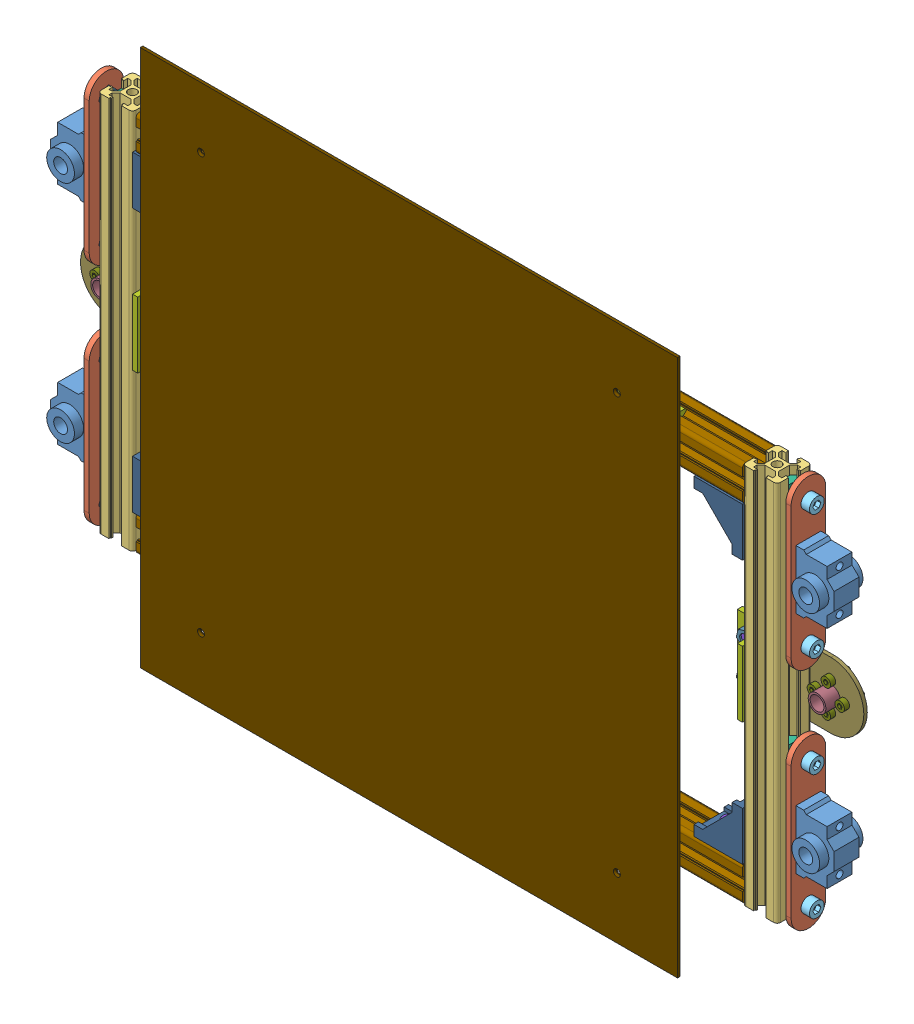
SolidWorks assembly 023Z轴平台-1, configuration 默认. Lengths in mm.
Overall size (452 310 46.5).
135 component instances, 18 part files, 83 mates.
Components (placement in the parent):
- SCS箱式直线两孔光轴短滑块SCS8-1: SCS箱式直线两孔光轴短滑块SCS8 [默认] at (43.7707 34.0892 10.8311) x (0 1 0) z (1 0 0) size (34 25 22)
- 不锈钢钢片件-1: 不锈钢钢片件 [默认] at (15.359 -82.3814 20.8311) x (0 1 0) z (0 0 1) size (96 3 20)
- 不锈钢钢片件-2: 不锈钢钢片件 [默认] at (15.359 -212.3814 20.8311) x (0 1 0) z (0 0 1) size (96 3 20)
- SCS箱式直线两孔光轴短滑块SCS8-2: SCS箱式直线两孔光轴短滑块SCS8 [默认] at (43.7707 -95.9108 10.8311) x (0 1 0) z (1 0 0) size (34 25 22)
- OB6_2020_220-1: OB6_2020_220 [默认] at (-2.641 10.6186 10.8311) x (1 0 0) z (0 -1 0) size (20 20 220)
- M4_10-1: M4_10 [默认] at (22.359 -22.3814 10.8311) x (0 1 0) z (0 0 1) size (7 13.91 7)
- M4_10-2: M4_10 [默认] at (22.359 -46.3814 10.8311) x (0 1 0) z (0 0 1) size (7 13.91 7)
- M5_12-1: M5_12 [默认] at (3.359 1.6186 10.8311) x (0 -1 0) z (0 0 1) size (8.5 16.91 8.5)
- M5_12-5: M5_12 [默认] at (3.359 -70.3814 10.8311) x (0 -1 0) z (0 0 1) size (8.5 16.91 8.5)
- 欧标20M5滑块螺母-1: 欧标20M5滑块螺母 [默认] at (2.259 6.3686 15.5811) x (0 -1 0) z (0 0 1) size (9.5 4.5 9.5)
- 欧标20M5滑块螺母-2: 欧标20M5滑块螺母 [默认] at (2.259 -65.6314 15.5811) x (0 -1 0) z (0 0 1) size (9.5 4.5 9.5)
- 欧标20M5滑块螺母-3: 欧标20M5滑块螺母 [默认] at (2.259 -195.6314 15.5811) x (0 -1 0) z (0 0 1) size (9.5 4.5 9.5)
- 欧标20M5滑块螺母-4: 欧标20M5滑块螺母 [默认] at (2.259 -123.6314 15.5811) x (0 -1 0) z (0 0 1) size (9.5 4.5 9.5)
- M5_12-6: M5_12 [默认] at (3.359 -200.3814 10.8311) x (0 -1 0) z (0 0 1) size (8.5 16.91 8.5)
- M5_12-4: M5_12 [默认] at (3.359 -128.3814 10.8311) x (0 -1 0) z (0 0 1) size (8.5 16.91 8.5)
- M4_10-3: M4_10 [默认] at (22.359 -176.3814 10.8311) x (0 1 0) z (0 0 1) size (7 13.91 7)
- M4_10-4: M4_10 [默认] at (22.359 -152.3814 10.8311) x (0 1 0) z (0 0 1) size (7 13.91 7)
- 可调平行连接角件2040_90度直角-1: 可调平行连接角件2040_90度直角 [默认] at (-12.641 -118.3814 0.8311) x (0 1 0) z (1 0 0) size (38 20 20)
- M5_8-5: M5_8 [默认] at (-7.641 -109.3814 10.8311) x (0 1 0) z (0 0 1) size (8.5 12.91 8.5)
- M5_8-6: M5_8 [默认] at (-7.641 -89.3814 10.8311) x (0 1 0) z (0 0 1) size (8.5 12.91 8.5)
- 欧标20M5滑块螺母-5: 欧标20M5滑块螺母 [默认] at (-7.541 -114.1314 15.5811) x (0 1 0) z (0 0 1) size (9.5 4.5 9.5)
- 欧标20M5滑块螺母-6: 欧标20M5滑块螺母 [默认] at (-7.541 -94.1314 15.5811) x (0 1 0) z (0 0 1) size (9.5 4.5 9.5)
- M5_12-7: M5_12 [默认] at (-380.641 -200.3814 10.8311) x (0 1 0) z (0 0 1) size (8.5 16.91 8.5)
- M4_10-5: M4_10 [默认] at (-399.641 -176.3814 10.8311) x (0 1 0) z (0 0 -1) size (7 13.91 7)
- 欧标20M5滑块螺母-7: 欧标20M5滑块螺母 [默认] at (-379.541 -65.6314 6.0811) x (0 -1 0) z (0 0 -1) size (9.5 4.5 9.5)
- M5_12-8: M5_12 [默认] at (-380.641 -70.3814 10.8311) x (0 1 0) z (0 0 1) size (8.5 16.91 8.5)
- M5_12-9: M5_12 [默认] at (-380.641 -128.3814 10.8311) x (0 1 0) z (0 0 1) size (8.5 16.91 8.5)
- 欧标20M5滑块螺母-8: 欧标20M5滑块螺母 [默认] at (-379.541 -123.6314 6.0811) x (0 -1 0) z (0 0 -1) size (9.5 4.5 9.5)
- 欧标20M5滑块螺母-9: 欧标20M5滑块螺母 [默认] at (-379.541 -195.6314 6.0811) x (0 -1 0) z (0 0 -1) size (9.5 4.5 9.5)
- M4_10-6: M4_10 [默认] at (-399.641 -152.3814 10.8311) x (0 1 0) z (0 0 -1) size (7 13.91 7)
- 欧标20M5滑块螺母-10: 欧标20M5滑块螺母 [默认] at (-379.541 6.3686 6.0811) x (0 -1 0) z (0 0 -1) size (9.5 4.5 9.5)
- M4_10-7: M4_10 [默认] at (-399.641 -46.3814 10.8311) x (0 1 0) z (0 0 -1) size (7 13.91 7)
- OB6_2020_220-2: OB6_2020_220 [默认] at (-374.641 -209.3814 10.8311) x (-1 0 0) z (0 1 0) size (20 20 220)
- SCS箱式直线两孔光轴短滑块SCS8-3: SCS箱式直线两孔光轴短滑块SCS8 [默认] at (-421.0528 -232.8519 10.8311) x (0 -1 0) z (-1 0 0) size (34 25 22)
- 不锈钢钢片件-3: 不锈钢钢片件 [默认] at (-392.641 -212.3814 0.8311) x (0 1 0) z (0 0 -1) size (96 3 20)
- 不锈钢钢片件-4: 不锈钢钢片件 [默认] at (-392.641 -82.3814 0.8311) x (0 1 0) z (0 0 -1) size (96 3 20)
- 欧标20M5滑块螺母-11: 欧标20M5滑块螺母 [默认] at (-369.741 -114.1314 6.0811) x (0 1 0) z (0 0 -1) size (9.5 4.5 9.5)
- M5_8-10: M5_8 [默认] at (-369.641 -89.3814 10.8311) x (0 -1 0) z (0 0 1) size (8.5 12.91 8.5)
- M5_8-11: M5_8 [默认] at (-369.641 -109.3814 10.8311) x (0 -1 0) z (0 0 1) size (8.5 12.91 8.5)
- M5_12-12: M5_12 [默认] at (-380.641 1.6186 10.8311) x (0 1 0) z (0 0 1) size (8.5 16.91 8.5)
- M4_10-8: M4_10 [默认] at (-399.641 -22.3814 10.8311) x (0 1 0) z (0 0 -1) size (7 13.91 7)
- 欧标20M5滑块螺母-12: 欧标20M5滑块螺母 [默认] at (-369.741 -94.1314 6.0811) x (0 1 0) z (0 0 -1) size (9.5 4.5 9.5)
- SCS箱式直线两孔光轴短滑块SCS8-4: SCS箱式直线两孔光轴短滑块SCS8 [默认] at (-421.0528 -102.8519 10.8311) x (0 -1 0) z (-1 0 0) size (34 25 22)
- 可调平行连接角件2040_90度直角-2: 可调平行连接角件2040_90度直角 [默认] at (-364.641 -80.3814 0.8311) x (0 -1 0) z (-1 0 0) size (38 20 20)
- OB6_2020_350-1: OB6_2020_350 [默认] at (-362.641 0.6186 10.8311) x (0 0 -1) z (1 0 0) size (20 20 350)
- OB6_2020_350-2: OB6_2020_350 [默认] at (-12.641 -199.3814 10.8311) x (0 0 -1) z (-1 0 0) size (20 20 350)
- 20角件加螺丝-1: 20角件加螺丝 [默认] at (-24.6902 -25.7024 40.3311) x (0 -1 0) z (0 0 -1) size (34 34 20)
  - 角件20-1: 角件20 [默认] at (-16.321 -12.0491 19.5) size (29.5 29.5 20)
  - 欧标20M5T形螺母-1: 欧标20M5T形螺母 [默认] at (3.679 -18.0491 34.5) x (0 0 -1) z (1 0 0) size (10 4.5 6)
  - M5_8-1: M5_8 [默认] at (0.679 -16.0491 29.5) size (8.5 12.91 8.5)
  - 欧标20M5T形螺母-2: 欧标20M5T形螺母 [默认] at (-22.321 1.9509 34.5) x (0 0 -1) z (0 -1 0) size (10 4.5 6)
  - M5_8-2: M5_8 [默认] at (-20.321 4.9509 29.5) x (0 -1 0) z (0 0 1) size (8.5 12.91 8.5)
- 20角件加螺丝-2: 20角件加螺丝 [默认] at (-352.5919 -25.7024 -18.6689) x (0 -1 0) z (0 0 1) size (34 34 20)
  - 角件20-1: 角件20 [默认] at (-16.321 -12.0491 19.5) size (29.5 29.5 20)
  - 欧标20M5T形螺母-1: 欧标20M5T形螺母 [默认] at (3.679 -18.0491 34.5) x (0 0 -1) z (1 0 0) size (10 4.5 6)
  - M5_8-1: M5_8 [默认] at (0.679 -16.0491 29.5) size (8.5 12.91 8.5)
  - 欧标20M5T形螺母-2: 欧标20M5T形螺母 [默认] at (-22.321 1.9509 34.5) x (0 0 -1) z (0 -1 0) size (10 4.5 6)
  - M5_8-2: M5_8 [默认] at (-20.321 4.9509 29.5) x (0 -1 0) z (0 0 1) size (8.5 12.91 8.5)
- 20角件加螺丝-3: 20角件加螺丝 [默认] at (-24.6902 -173.0603 -18.6689) x (0 1 0) z (0 0 1) size (34 34 20)
  - 角件20-1: 角件20 [默认] at (-16.321 -12.0491 19.5) size (29.5 29.5 20)
  - 欧标20M5T形螺母-1: 欧标20M5T形螺母 [默认] at (3.679 -18.0491 34.5) x (0 0 -1) z (1 0 0) size (10 4.5 6)
  - M5_8-1: M5_8 [默认] at (0.679 -16.0491 29.5) size (8.5 12.91 8.5)
  - 欧标20M5T形螺母-2: 欧标20M5T形螺母 [默认] at (-22.321 1.9509 34.5) x (0 0 -1) z (0 -1 0) size (10 4.5 6)
  - M5_8-2: M5_8 [默认] at (-20.321 4.9509 29.5) x (0 -1 0) z (0 0 1) size (8.5 12.91 8.5)
- 20角件加螺丝-4: 20角件加螺丝 [默认] at (-352.5919 -173.0603 40.3311) x (0 1 0) z (0 0 -1) size (34 34 20)
  - 角件20-1: 角件20 [默认] at (-16.321 -12.0491 19.5) size (29.5 29.5 20)
  - 欧标20M5T形螺母-1: 欧标20M5T形螺母 [默认] at (3.679 -18.0491 34.5) x (0 0 -1) z (1 0 0) size (10 4.5 6)
  - M5_8-1: M5_8 [默认] at (0.679 -16.0491 29.5) size (8.5 12.91 8.5)
  - 欧标20M5T形螺母-2: 欧标20M5T形螺母 [默认] at (-22.321 1.9509 34.5) x (0 0 -1) z (0 -1 0) size (10 4.5 6)
  - M5_8-2: M5_8 [默认] at (-20.321 4.9509 29.5) x (0 -1 0) z (0 0 1) size (8.5 12.91 8.5)
- Z轴丝杆连接片-1: Z轴丝杆连接片 [默认] at (18.359 -99.3814 0.8311) x (-1 0 0) z (0 -1 0) size (69 2 38)
- 8MM丝杆T形螺母-1: 8MM丝杆T形螺母 [默认] at (18.359 -99.3814 8.8311) x (1 0 0) z (0 1 0) size (22 15.5 22)
- Z轴丝杆连接片-2: Z轴丝杆连接片 [默认] at (-395.641 -99.3814 0.8311) x (1 0 0) z (0 1 0) size (69 2 38)
- 8MM丝杆T形螺母-2: 8MM丝杆T形螺母 [默认] at (-395.641 -99.3814 8.8311) x (-1 0 0) z (0 -1 0) size (22 15.5 22)
- M5螺母-1: M5螺母 [默认] at (12.359 1.6186 10.8311) x (0 1 0) z (0 0 1) size (8.9 3.9 8.95)
- M5螺母-2: M5螺母 [默认] at (12.359 -70.3814 10.8311) x (0 1 0) z (0 0 1) size (8.9 3.9 8.95)
- M5螺母-3: M5螺母 [默认] at (12.359 -128.3814 10.8311) x (0 1 0) z (0 0 1) size (8.9 3.9 8.95)
- M5螺母-4: M5螺母 [默认] at (12.359 -200.3814 10.8311) x (0 1 0) z (0 0 1) size (8.9 3.9 8.95)
- M5螺母-5: M5螺母 [默认] at (-385.741 1.6186 10.8311) x (0 1 0) z (0 0 1) size (8.9 3.9 8.95)
- M5螺母-6: M5螺母 [默认] at (-385.741 -70.3814 10.8311) x (0 1 0) z (0 0 1) size (8.9 3.9 8.95)
- M5螺母-7: M5螺母 [默认] at (-385.741 -128.3814 10.8311) x (0 1 0) z (0 0 1) size (8.9 3.9 8.95)
- M5螺母-8: M5螺母 [默认] at (-385.741 -200.3814 10.8311) x (0 1 0) z (0 0 1) size (8.9 3.9 8.95)
- M5_6-13: M5_6 [默认] at (-2.541 -109.1314 4.8311) x (1 0 0) z (0 1 0) size (8.5 10.91 8.5)
- 欧标20M5滑块螺母-13: 欧标20M5滑块螺母 [默认] at (-7.291 -113.8814 5.9311) x (0 1 0) z (-1 0 0) size (9.5 4.5 9.5)
- 欧标20M5滑块螺母-14: 欧标20M5滑块螺母 [默认] at (-7.291 -93.8814 5.9311) x (0 1 0) z (-1 0 0) size (9.5 4.5 9.5)
- M5_6-14: M5_6 [默认] at (-2.541 -89.1314 4.8311) x (1 0 0) z (0 1 0) size (8.5 10.91 8.5)
- M5_6-15: M5_6 [默认] at (-374.741 -109.1314 4.8311) x (-1 0 0) z (0 -1 0) size (8.5 10.91 8.5)
- 欧标20M5滑块螺母-15: 欧标20M5滑块螺母 [默认] at (-379.491 -113.8814 5.9311) x (0 1 0) z (-1 0 0) size (9.5 4.5 9.5)
- 欧标20M5滑块螺母-16: 欧标20M5滑块螺母 [默认] at (-379.491 -93.8814 5.9311) x (0 1 0) z (-1 0 0) size (9.5 4.5 9.5)
- M5_6-16: M5_6 [默认] at (-374.741 -89.1314 4.8311) x (-1 0 0) z (0 -1 0) size (8.5 10.91 8.5)
- M5_8-15: M5_8 [默认] at (-24.891 -109.3814 6.8311) x (1 0 0) z (0 1 0) size (8.5 12.91 8.5)
- M5螺母-9: M5螺母 [默认] at (-24.891 -109.3814 3.8311) x (1 0 0) z (0 -1 0) size (8.9 3.9 8.95)
- M5螺母-10: M5螺母 [默认] at (-24.891 -89.3814 3.8311) x (1 0 0) z (0 -1 0) size (8.9 3.9 8.95)
- M5_8-16: M5_8 [默认] at (-24.891 -89.3814 6.8311) x (1 0 0) z (0 1 0) size (8.5 12.91 8.5)
- M5_8-17: M5_8 [默认] at (-352.391 -109.3814 6.8311) x (-1 0 0) z (0 -1 0) size (8.5 12.91 8.5)
- M5螺母-11: M5螺母 [默认] at (-352.391 -109.3814 7.7311) x (-1 0 0) z (0 -1 0) size (8.9 3.9 8.95)
- M5螺母-12: M5螺母 [默认] at (-352.391 -89.3814 7.7311) x (-1 0 0) z (0 -1 0) size (8.9 3.9 8.95)
- M5_8-18: M5_8 [默认] at (-352.391 -89.3814 6.8311) x (-1 0 0) z (0 -1 0) size (8.5 12.91 8.5)
- M3_10-1: M3_10 [默认] at (18.359 -91.3814 -9.1689) x (1 0 0) z (0 -1 0) size (5.5 12.93 5.5)
- M3_10-2: M3_10 [默认] at (26.359 -99.3814 -9.1689) x (1 0 0) z (0 -1 0) size (5.5 12.93 5.5)
- M3_10-3: M3_10 [默认] at (18.359 -107.3814 -9.1689) x (1 0 0) z (0 -1 0) size (5.5 12.93 5.5)
- M3_10-4: M3_10 [默认] at (10.359 -99.3814 -9.1689) x (1 0 0) z (0 -1 0) size (5.5 12.93 5.5)
- M3尼龙螺母-1: M3尼龙螺母 [默认] at (26.359 -99.3814 -4.6689) x (0.972316 -0.233668 0) z (0.233668 0.972316 0) size (6.88 4 6.18)
- M3尼龙螺母-2: M3尼龙螺母 [默认] at (10.359 -99.3814 -4.6689) x (0.970018 -0.243033 0) z (0.243033 0.970018 0) size (6.88 4 6.18)
- M3尼龙螺母-3: M3尼龙螺母 [默认] at (18.359 -91.3814 -4.6689) x (0.939563 0.342377 0) z (-0.342377 0.939563 0) size (6.88 4 6.18)
- M3尼龙螺母-4: M3尼龙螺母 [默认] at (18.359 -107.3814 -4.6689) x (0.981669 0.190593 0) z (-0.190593 0.981669 0) size (6.88 4 6.18)
- M3_10-5: M3_10 [默认] at (-395.641 -91.3814 -9.1689) x (-1 0 0) z (0 1 0) size (5.5 12.93 5.5)
- M3_10-6: M3_10 [默认] at (-403.641 -99.3814 -9.1689) x (-1 0 0) z (0 1 0) size (5.5 12.93 5.5)
- M3_10-7: M3_10 [默认] at (-395.641 -107.3814 -9.1689) x (-1 0 0) z (0 1 0) size (5.5 12.93 5.5)
- M3_10-8: M3_10 [默认] at (-387.641 -99.3814 -9.1689) x (-1 0 0) z (0 1 0) size (5.5 12.93 5.5)
- M3尼龙螺母-5: M3尼龙螺母 [默认] at (-387.641 -99.3814 -8.6689) x (-0.970018 -0.243033 0) z (-0.243033 0.970018 0) size (6.88 4 6.18)
- M3尼龙螺母-6: M3尼龙螺母 [默认] at (-403.641 -99.3814 -8.6689) x (-0.972316 -0.233668 0) z (-0.233668 0.972316 0) size (6.88 4 6.18)
- M3尼龙螺母-7: M3尼龙螺母 [默认] at (-395.641 -91.3814 -8.6689) x (-0.939563 0.342377 0) z (0.342377 0.939563 0) size (6.88 4 6.18)
- M3尼龙螺母-8: M3尼龙螺母 [默认] at (-395.641 -107.3814 -8.6689) x (-0.981669 0.190593 0) z (0.190593 0.981669 0) size (6.88 4 6.18)
- 热床-1: 热床 [默认] at (-188.641 -93.3814 35.8311) x (1 0 0) z (0 -1 0) size (310 1.5 310)
- 可调平行连接角件2040_90度直角-3: 可调平行连接角件2040_90度直角 [默认] at (-317.3176 -203.3814 20.8311) x (1 0 0) z (0 1 0) size (38 20 20)
- M5_8-19: M5_8 [默认] at (-308.3176 -198.3814 10.8311) x (0 0 1) z (1 0 0) size (8.5 12.91 8.5)
- M5_8-20: M5_8 [默认] at (-288.3176 -198.3814 10.8311) x (-1 0 0) z (0 0 1) size (8.5 12.91 8.5)
- 欧标20M5滑块螺母-17: 欧标20M5滑块螺母 [默认] at (-303.5676 -198.2814 15.5811) x (-1 0 0) z (0 0 1) size (9.5 4.5 9.5)
- 欧标20M5滑块螺母-18: 欧标20M5滑块螺母 [默认] at (-283.5676 -198.2814 15.5811) x (-1 0 0) z (0 0 1) size (9.5 4.5 9.5)
- 欧标20M5滑块螺母-19: 欧标20M5滑块螺母 [默认] at (-93.7145 -198.2814 6.0811) x (1 0 0) z (0 0 -1) size (9.5 4.5 9.5)
- 欧标20M5滑块螺母-20: 欧标20M5滑块螺母 [默认] at (-73.7145 -198.2814 6.0811) x (1 0 0) z (0 0 -1) size (9.5 4.5 9.5)
- M5_8-21: M5_8 [默认] at (-88.9645 -198.3814 10.8311) x (1 0 0) z (0 0 -1) size (8.5 12.91 8.5)
- M5_8-22: M5_8 [默认] at (-68.9645 -198.3814 10.8311) x (0 0 1) z (1 0 0) size (8.5 12.91 8.5)
- 可调平行连接角件2040_90度直角-4: 可调平行连接角件2040_90度直角 [默认] at (-97.9645 -203.3814 20.8311) x (1 0 0) z (0 1 0) size (38 20 20)
- 欧标20M5滑块螺母-21: 欧标20M5滑块螺母 [默认] at (-283.5676 -0.4814 6.0811) x (-1 0 0) z (0 0 -1) size (9.5 4.5 9.5)
- 欧标20M5滑块螺母-22: 欧标20M5滑块螺母 [默认] at (-303.5676 -0.4814 6.0811) x (-1 0 0) z (0 0 -1) size (9.5 4.5 9.5)
- M5_8-23: M5_8 [默认] at (-288.3176 -0.3814 10.8311) x (-1 0 0) z (0 0 -1) size (8.5 12.91 8.5)
- M5_8-24: M5_8 [默认] at (-308.3176 -0.3814 10.8311) x (0 0 1) z (-1 0 0) size (8.5 12.91 8.5)
- 可调平行连接角件2040_90度直角-5: 可调平行连接角件2040_90度直角 [默认] at (-279.3176 4.6186 20.8311) x (-1 0 0) z (0 -1 0) size (38 20 20)
- 欧标20M5滑块螺母-23: 欧标20M5滑块螺母 [默认] at (-93.7145 -0.4814 15.5811) size (9.5 4.5 9.5)
- 欧标20M5滑块螺母-24: 欧标20M5滑块螺母 [默认] at (-73.7145 -0.4814 15.5811) size (9.5 4.5 9.5)
- M5_8-25: M5_8 [默认] at (-88.9645 -0.3814 10.8311) size (8.5 12.91 8.5)
- M5_8-26: M5_8 [默认] at (-68.9645 -0.3814 10.8311) x (0 0 1) z (-1 0 0) size (8.5 12.91 8.5)
- 可调平行连接角件2040_90度直角-6: 可调平行连接角件2040_90度直角 [默认] at (-59.9645 4.6186 20.8311) x (-1 0 0) z (0 -1 0) size (38 20 20)
Mates (geometry in assembly coordinates):
- 重合1: coincident: plane of SCS箱式直线两孔光轴短滑块SCS8-1 through (15.359 -51.3814 18.0311) normal (-1 0 0); plane of 不锈钢钢片件-1 through (15.359 3.6186 10.8311) normal (1 0 0)
- 同心1: concentric: cylinder of SCS箱式直线两孔光轴短滑块SCS8-1 through (37.359 -46.3814 10.8311) axis (1 0 0) radius 2; cylinder of 不锈钢钢片件-1 through (12.359 -46.3814 10.8311) axis (1 0 0) radius 2.5
- 同心2: concentric: cylinder of SCS箱式直线两孔光轴短滑块SCS8-1 through (37.359 -22.3814 10.8311) axis (1 0 0) radius 2; cylinder of 不锈钢钢片件-1 through (12.359 -22.3814 10.8311) axis (1 0 0) radius 2.5
- 同心3: concentric: cylinder of SCS箱式直线两孔光轴短滑块SCS8-1 through (37.359 -22.3814 10.8311) axis (1 0 0) radius 2; cylinder of M4_10-1 through (12.359 -22.3814 10.8311) axis (1 0 0) radius 2
- 同心4: concentric: cylinder of SCS箱式直线两孔光轴短滑块SCS8-1 through (37.359 -46.3814 10.8311) axis (1 0 0) radius 2; cylinder of M4_10-2 through (12.359 -46.3814 10.8311) axis (1 0 0) radius 2
- 重合2: coincident: plane of assembly; plane of assembly; plane of 不锈钢钢片件-1 through (12.359 3.6186 10.8311) normal (-1 0 0); plane of M4_10-1 through (12.359 -22.3814 10.8311) normal (1 0 0)
- 重合3: coincident: plane of assembly; plane of assembly; plane of 不锈钢钢片件-1 through (12.359 3.6186 10.8311) normal (-1 0 0); plane of M4_10-2 through (12.359 -46.3814 10.8311) normal (1 0 0)
- 同心5: concentric: cylinder of assembly; cylinder of assembly; cylinder of 不锈钢钢片件-1 through (12.359 1.6186 10.8311) axis (1 0 0) radius 2.5; cylinder of M5_12-1 through (15.359 1.6186 10.8311) axis (-1 0 0) radius 2.5
- 同心6: concentric: cylinder of assembly; cylinder of assembly; cylinder of 不锈钢钢片件-1 through (12.359 -70.3814 10.8311) axis (1 0 0) radius 2.5; cylinder of M5_12-5 through (15.359 -70.3814 10.8311) axis (-1 0 0) radius 2.5
- 重合4: coincident: plane of assembly; plane of assembly; plane of 不锈钢钢片件-1 through (15.359 3.6186 10.8311) normal (1 0 0); plane of M5_12-5 through (15.359 -70.3814 10.8311) normal (-1 0 0)
- 重合5: coincident: plane of assembly; plane of assembly; plane of 不锈钢钢片件-1 through (15.359 3.6186 10.8311) normal (1 0 0); plane of M5_12-1 through (15.359 1.6186 10.8311) normal (-1 0 0)
- 同心7: concentric: cylinder of assembly; cylinder of assembly; cylinder of M5_12-1 through (15.359 1.6186 10.8311) axis (-1 0 0) radius 2.5; cylinder of 欧标20M5滑块螺母-1 through (2.259 1.6186 10.8311) axis (1 0 0) radius 2.5
- 同心8: concentric: cylinder of assembly; cylinder of assembly; cylinder of M5_12-5 through (15.359 -70.3814 10.8311) axis (-1 0 0) radius 2.5; cylinder of 欧标20M5滑块螺母-2 through (2.259 -70.3814 10.8311) axis (1 0 0) radius 2.5
- 距离1: distance = 6.8 mm: plane of assembly; plane of assembly; plane of 不锈钢钢片件-1 through (12.359 3.6186 10.8311) normal (-1 0 0); plane of 欧标20M5滑块螺母-2 through (5.559 -65.6314 15.5811) normal (1 0 0)
- 距离2: distance = 6.8 mm: plane of assembly; plane of assembly; plane of 欧标20M5滑块螺母-1 through (5.559 6.3686 15.5811) normal (1 0 0); plane of 不锈钢钢片件-1 through (12.359 3.6186 10.8311) normal (-1 0 0)
- 重合7: coincident: plane of 不锈钢钢片件-1 through (12.359 -72.3814 20.8311) normal (0 0 1); plane of ? through (0.959 -203.3814 20.8311) normal (0 0 1)
- 距离3: distance = 3 mm: plane of assembly; cylinder of assembly; plane of OB6_2020_220-1 through (-2.641 10.6186 10.8311) normal (0 1 0); cylinder of 不锈钢钢片件-1 through (12.359 3.6186 10.8311) axis (1 0 0) radius 10
- 同心9: concentric: cylinder of ? through (-15.641 -83.3814 10.8311) axis (1 0 0) radius 2.5; cylinder of ? through (-7.541 -83.3814 10.8311) axis (-1 0 0) radius 2.5
- 同心10: concentric: cylinder of ? through (-32.641 -83.3814 10.8311) axis (1 0 0) radius 2.75; cylinder of ? through (-15.641 -83.3814 10.8311) axis (1 0 0) radius 2.5
- 重合8: coincident: plane of ? through (-15.641 -74.3814 3.8311) normal (-1 0 0); plane of ? through (-15.641 -83.3814 10.8311) normal (1 0 0)
- 距离4: distance = 1.8 mm: plane of assembly; plane of assembly; plane of 可调平行连接角件2040_90度直角-1 through (-12.641 -80.3814 20.8311) normal (1 0 0); plane of 欧标20M5滑块螺母-6 through (-10.841 -94.1314 15.5811) normal (-1 0 0)
- 同心11: concentric: cylinder of ? through (-32.641 -103.3814 10.8311) axis (1 0 0) radius 2.75; cylinder of ? through (-15.641 -103.3814 10.8311) axis (1 0 0) radius 2.5
- 重合9: coincident: plane of ? through (-15.641 -74.3814 3.8311) normal (-1 0 0); plane of ? through (-15.641 -103.3814 10.8311) normal (1 0 0)
- 同心12: concentric: cylinder of ? through (-15.641 -103.3814 10.8311) axis (1 0 0) radius 2.5; cylinder of ? through (-7.541 -103.3814 10.8311) axis (-1 0 0) radius 2.5
- 距离5: distance = 1.8 mm: plane of assembly; plane of assembly; plane of 欧标20M5滑块螺母-5 through (-10.841 -114.1314 15.5811) normal (-1 0 0); plane of 可调平行连接角件2040_90度直角-1 through (-12.641 -80.3814 20.8311) normal (1 0 0)
- 重合11: coincident: plane of ? through (-6.241 -203.3814 0.8311) normal (0 0 -1); plane of ? through (-12.641 -74.3814 0.8311) normal (0 0 -1)
- 重合12: coincident: plane of ? through (-12.641 -203.3814 7.2311) normal (-1 0 0); plane of ? through (-12.641 -74.3814 20.8311) normal (1 0 0)
- 距离6: distance = 91 mm: plane of assembly; plane of assembly; plane of OB6_2020_220-1 through (-2.641 -209.3814 10.8311) normal (0 -1 0); plane of 可调平行连接角件2040_90度直角-1 through (-12.641 -118.3814 0.8311) normal (0 -1 0)
- 重合13: coincident: plane of ? through (-6.241 -203.3814 20.8311) normal (0 0 1); plane of ? through (-12.641 3.0186 20.8311) normal (0 0 1)
- 重合16: coincident: plane of ? through (-12.641 -203.3814 7.2311) normal (-1 0 0); plane of ? through (-12.641 -3.3814 0.8311) normal (1 0 0)
- 重合17: coincident: plane of ? through (-12.641 -3.3814 14.4311) normal (0 -1 0); plane of ? through (-12.641 -3.3814 0.8311) normal (0 1 0)
- 重合18: coincident: plane of ? through (-6.241 -203.3814 20.8311) normal (0 0 1); plane of ? through (-12.641 -3.3814 20.8311) normal (0 0 1)
- 重合19: coincident: plane of ? through (0.959 -203.3814 0.8311) normal (0 0 -1); plane of ? through (18.359 -93.3814 0.8311) normal (0 0 1)
- 重合20: coincident: plane of ? through (18.359 -93.3814 -1.1689) normal (0 0 -1); plane of ? through (18.359 -93.3814 -1.1689) normal (0 0 1)
- 同心13: concentric: cylinder of ? through (18.359 -93.3814 0.8311) axis (0 0 -1) radius 5.5; cylinder of ? through (18.359 -93.3814 -1.1689) axis (0 0 1) radius 5.1
- 同心14: concentric: cylinder of ? through (26.359 -93.3814 0.8311) axis (0 0 -1) radius 1.65; cylinder of ? through (26.359 -93.3814 8.8311) axis (0 0 -1) radius 1.75
- 重合21: coincident: plane of ? through (-12.641 -74.3814 0.8311) normal (0 1 0); plane of ? through (18.359 -74.3814 -1.1689) normal (0 1 0)
- 距离7: distance = 5.5 mm: plane of assembly; cylinder of assembly; plane of OB6_2020_220-1 through (7.359 -209.3814 7.2311) normal (1 0 0); cylinder of Z轴丝杆连接片-1 through (18.359 -99.3814 0.8311) axis (0 0 -1) radius 5.5
- 重合22: coincident: plane of assembly; plane of assembly; plane of 不锈钢钢片件-1 through (12.359 3.6186 10.8311) normal (-1 0 0); plane of M5螺母-1 through (12.359 1.6186 10.8311) normal (1 0 0)
- 同心15: concentric: cylinder of assembly; cylinder of assembly; cylinder of M5_12-1 through (15.359 1.6186 10.8311) axis (-1 0 0) radius 2.5; cylinder of M5螺母-1 through (8.459 1.6186 10.8311) axis (1 0 0) radius 2.5
- 距离8: distance = 1.8 mm: plane of assembly; plane of assembly; plane of OB6_2020_220-1 through (7.359 -209.3814 14.4311) normal (1 0 0); plane of 欧标20M5滑块螺母-1 through (5.559 6.3686 15.5811) normal (1 0 0)
- 同心16: concentric: cylinder of assembly; cylinder of assembly; cylinder of M5_12-5 through (15.359 -70.3814 10.8311) axis (-1 0 0) radius 2.5; cylinder of M5螺母-2 through (8.459 -70.3814 10.8311) axis (1 0 0) radius 2.5
- 重合23: coincident: plane of assembly; plane of assembly; plane of 不锈钢钢片件-1 through (12.359 3.6186 10.8311) normal (-1 0 0); plane of M5螺母-2 through (12.359 -70.3814 10.8311) normal (1 0 0)
- 重合24: coincident: plane of ? through (18.359 -93.3814 -1.1689) normal (0 0 -1); plane of ? through (-2.541 -103.1314 -1.1689) normal (0 0 1)
- 同心17: concentric: cylinder of ? through (-2.541 -103.1314 -1.1689) axis (0 0 1) radius 2.5; cylinder of ? through (-2.541 -103.1314 5.9311) axis (0 0 -1) radius 2.5
- 相切1: tangent: plane of ? through (-24.891 -100.6314 0.8311) normal (0 -1 0); cylinder of ? through (-2.541 -103.1314 -1.1689) axis (0 0 1) radius 2.5
- 距离9: distance = 1.8 mm: plane of assembly; plane of assembly; plane of OB6_2020_220-1 through (0.959 -209.3814 0.8311) normal (0 0 -1); plane of 欧标20M5滑块螺母-13 through (-7.291 -113.8814 2.6311) normal (0 0 -1)
- 重合25: coincident: plane of ? through (0.459 -203.3814 2.6311) normal (-1 0 0); plane of ? through (0.459 -98.3814 1.4311) normal (1 0 0)
- 重合26: coincident: plane of ? through (18.359 -93.3814 -1.1689) normal (0 0 -1); plane of ? through (-24.891 -103.3814 -1.1689) normal (0 0 1)
- 同心18: concentric: cylinder of ? through (-24.891 -103.3814 0.8311) axis (0 0 -1) radius 2.75; cylinder of ? through (-24.891 -103.3814 -1.1689) axis (0 0 1) radius 2.5
- 重合27: coincident: plane of ? through (-32.641 -74.3814 3.8311) normal (0 0 1); plane of ? through (-24.891 -103.3814 3.8311) normal (0 0 -1)
- 同心19: concentric: cylinder of ? through (-24.891 -103.3814 -1.1689) axis (0 0 1) radius 2.5; cylinder of ? through (-24.891 -103.3814 7.7311) axis (0 0 -1) radius 2.5
- 重合28: coincident: plane of ? through (18.359 -93.3814 0.8311) normal (0 0 1); plane of ? through (18.359 -85.3814 0.8311) normal (0 0 -1)
- 同心20: concentric: cylinder of ? through (18.359 -85.3814 8.8311) axis (0 0 -1) radius 1.75; cylinder of ? through (18.359 -85.3814 0.8311) axis (0 0 -1) radius 1.5
- 重合29: coincident: plane of ? through (18.359 -93.3814 0.8311) normal (0 0 1); plane of ? through (26.359 -93.3814 0.8311) normal (0 0 -1)
- 同心21: concentric: cylinder of ? through (26.359 -93.3814 8.8311) axis (0 0 -1) radius 1.75; cylinder of ? through (26.359 -93.3814 0.8311) axis (0 0 -1) radius 1.5
- 重合30: coincident: plane of ? through (18.359 -93.3814 0.8311) normal (0 0 1); plane of ? through (18.359 -101.3814 0.8311) normal (0 0 -1)
- 同心22: concentric: cylinder of ? through (18.359 -101.3814 8.8311) axis (0 0 -1) radius 1.75; cylinder of ? through (18.359 -101.3814 0.8311) axis (0 0 -1) radius 1.5
- 重合31: coincident: plane of ? through (18.359 -93.3814 0.8311) normal (0 0 1); plane of ? through (10.359 -93.3814 0.8311) normal (0 0 -1)
- 同心23: concentric: cylinder of ? through (10.359 -93.3814 8.8311) axis (0 0 -1) radius 1.75; cylinder of ? through (10.359 -93.3814 0.8311) axis (0 0 -1) radius 1.5
- 重合32: coincident: plane of ? through (18.359 -93.3814 -4.6689) normal (0 0 -1); plane of ? through (26.359 -93.3814 -4.6689) normal (0 0 1)
- 同心24: concentric: cylinder of ? through (26.359 -93.3814 0.8311) axis (0 0 -1) radius 1.5; cylinder of ? through (26.359 -93.3814 -8.6689) axis (0 0 1) radius 1.5
- 重合33: coincident: plane of ? through (18.359 -93.3814 -4.6689) normal (0 0 -1); plane of ? through (18.359 -85.3814 -4.6689) normal (0 0 1)
- 同心25: concentric: cylinder of ? through (18.359 -85.3814 0.8311) axis (0 0 -1) radius 1.5; cylinder of ? through (18.359 -85.3814 -8.6689) axis (0 0 1) radius 1.5
- 重合34: coincident: plane of ? through (18.359 -93.3814 -4.6689) normal (0 0 -1); plane of ? through (18.359 -101.3814 -4.6689) normal (0 0 1)
- 同心26: concentric: cylinder of ? through (18.359 -101.3814 0.8311) axis (0 0 -1) radius 1.5; cylinder of ? through (18.359 -101.3814 -8.6689) axis (0 0 1) radius 1.5
- 重合35: coincident: plane of ? through (18.359 -93.3814 -4.6689) normal (0 0 -1); plane of ? through (10.359 -93.3814 -4.6689) normal (0 0 1)
- 同心27: concentric: cylinder of ? through (10.359 -93.3814 0.8311) axis (0 0 -1) radius 1.5; cylinder of ? through (10.359 -93.3814 -8.6689) axis (0 0 1) radius 1.5
- 重合36: coincident: plane of ? through (-2.641 16.6186 10.8311) normal (0 1 0); plane of ? through (-12.641 16.6186 14.4311) normal (0 1 0)
- 重合37: coincident: plane of ? through (-12.641 -203.3814 14.4311) normal (-1 0 0); plane of ? through (-12.641 6.6186 10.8311) normal (1 0 0)
- 距离10: distance = 15 mm: plane of assembly; plane of assembly; plane of 热床-1 through (-188.641 -93.3814 35.8311) normal (0 0 -1); plane of OB6_2020_350-2 through (-362.641 -195.7814 20.8311) normal (0 0 1)
- 距离11: distance = 155 mm: plane of assembly through (-188.641 0 0) normal (-1 0 0); plane of 热床-1 through (-33.641 61.6186 37.3311) normal (1 0 0); plane of assembly
- 距离12: distance = 155 mm: plane of assembly through (0 -99.3814 0) normal (0 -1 0); plane of 热床-1 through (-343.641 -248.3814 37.3311) normal (0 -1 0); plane of assembly
- 同心28: concentric: cylinder of assembly; cylinder of assembly; cylinder of M5_8-19 through (-308.3176 -206.3814 10.8311) axis (0 1 0) radius 2.5; cylinder of 欧标20M5滑块螺母-17 through (-308.3176 -198.2814 10.8311) axis (0 -1 0) radius 2.5
- 同心29: concentric: cylinder of assembly; cylinder of assembly; cylinder of M5_8-20 through (-288.3176 -206.3814 10.8311) axis (0 1 0) radius 2.5; cylinder of 欧标20M5滑块螺母-18 through (-288.3176 -198.2814 10.8311) axis (0 -1 0) radius 2.5
- 距离13: distance = 1.8 mm: plane of assembly; plane of assembly; plane of 可调平行连接角件2040_90度直角-3 through (-279.3176 -203.3814 0.8311) normal (0 1 0); plane of 欧标20M5滑块螺母-17 through (-303.5676 -201.5814 15.5811) normal (0 -1 0)
- 距离14: distance = 1.8 mm: plane of assembly; plane of assembly; plane of 可调平行连接角件2040_90度直角-3 through (-279.3176 -203.3814 0.8311) normal (0 1 0); plane of 欧标20M5滑块螺母-18 through (-283.5676 -201.5814 15.5811) normal (0 -1 0)
- 重合38: coincident: plane of assembly; plane of assembly; plane of 可调平行连接角件2040_90度直角-3 through (-279.3176 -206.3814 17.8311) normal (0 -1 0); plane of M5_8-20 through (-288.3176 -206.3814 10.8311) normal (0 1 0)
- 重合39: coincident: plane of assembly; plane of assembly; plane of 可调平行连接角件2040_90度直角-3 through (-279.3176 -206.3814 17.8311) normal (0 -1 0); plane of M5_8-19 through (-308.3176 -206.3814 10.8311) normal (0 1 0)
- 同心30: concentric: cylinder of assembly; cylinder of assembly; cylinder of 可调平行连接角件2040_90度直角-3 through (-308.3176 -223.3814 10.8311) axis (0 1 0) radius 2.75; cylinder of M5_8-19 through (-308.3176 -206.3814 10.8311) axis (0 1 0) radius 2.5
- 同心31: concentric: cylinder of assembly; cylinder of assembly; cylinder of 可调平行连接角件2040_90度直角-3 through (-288.3176 -223.3814 10.8311) axis (0 1 0) radius 2.75; cylinder of M5_8-20 through (-288.3176 -206.3814 10.8311) axis (0 1 0) radius 2.5
- 重合40: coincident: plane of ? through (-362.641 -203.3814 7.2311) normal (0 -1 0); plane of 可调平行连接角件2040_90度直角-3 through (-279.3176 -203.3814 0.8311) normal (0 1 0)
- 重合41: coincident: plane of ? through (-362.641 -196.9814 0.8311) normal (0 0 -1); plane of 可调平行连接角件2040_90度直角-3 through (-279.3176 -206.3814 0.8311) normal (0 0 -1)
